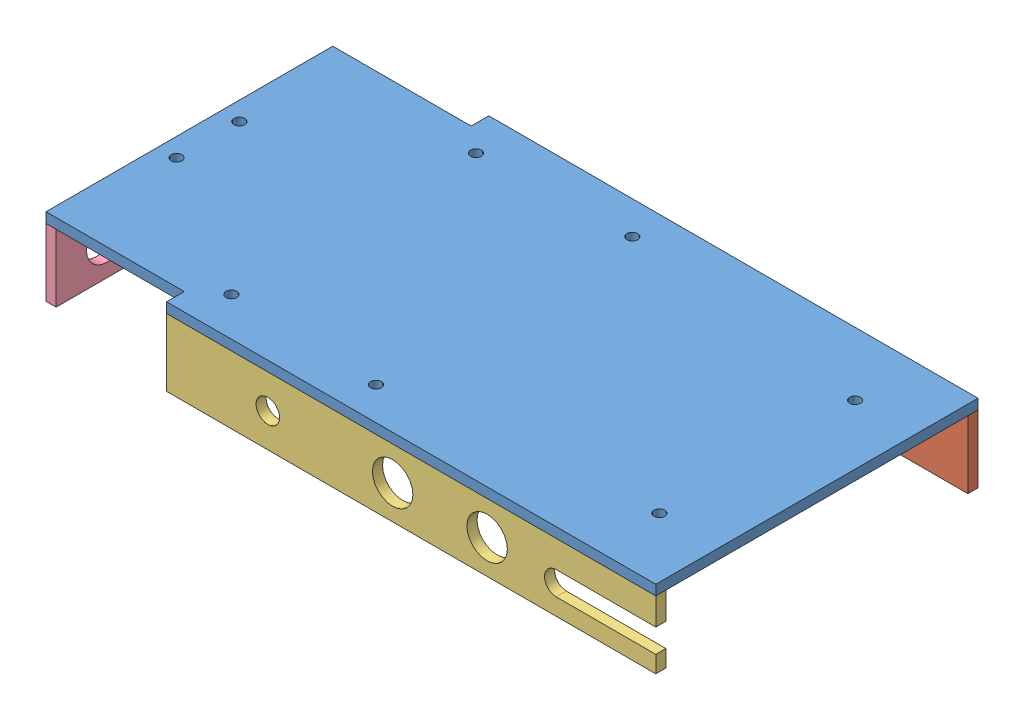
SolidWorks assembly base, configuration Default. Lengths in mm.
Overall size (186 23 95.5).
4 component instances, 4 part files, 7 mates.
Components (placement in the parent):
- base plate-1: base plate [Default] at (-22.9763 80.2104 200.6386) size (186 3 95.5)
- base_side_plate_L-1: base_side_plate_L [Default] at (18.0237 60.2104 105.1386) size (145 20 3)
- base_side_plate_R-1: base_side_plate_R [Default] at (18.0237 60.2104 197.6386) size (145 20 3)
- base_side_plate_back-1: base_side_plate_back [Default] at (-19.9763 60.2104 110.3886) x (0 0 1) z (-1 0 0) size (85 20 3)
Mates (geometry in assembly coordinates):
- Coincident1: coincident anti-aligned: plane of base plate-1 through (-22.9763 80.2104 200.6386) normal (0 -1 0); plane of side_plate_R-1 through (18.0237 80.2104 200.6386) normal (0 1 0)
- Coincident2: coincident aligned: line of base plate-1 through (163.0237 80.2104 200.6386) axis (0 0 -1); line of side_plate_R-1 through (163.0237 80.2104 200.6386) axis (0 0 -1)
- Coincident3: coincident aligned: line of base plate-1 through (18.0237 80.2104 200.6386) axis (1 0 0); line of side_plate_R-1 through (18.0237 80.2104 200.6386) axis (1 0 0)
- Coincident5: coincident aligned: line of base plate-1 through (-22.9763 80.2104 110.3886) axis (0 0 1); line of base_side_plate_back-1 through (-22.9763 80.2104 110.3886) axis (0 0 1)
- Coincident6: coincident aligned: line of base plate-1 through (-22.9763 80.2104 195.3886) axis (1 0 0); line of base_side_plate_back-1 through (-22.9763 80.2104 195.3886) axis (1 0 0)
- Coincident7: coincident aligned: line of base plate-1 through (163.0237 80.2104 105.1386) axis (-1 0 0); line of side_plate_L-1 through (163.0237 80.2104 105.1386) axis (-1 0 0)
- Coincident8: coincident aligned: line of base plate-1 through (163.0237 80.2104 200.6386) axis (0 0 -1); line of side_plate_L-1 through (163.0237 80.2104 108.1386) axis (0 0 -1)
